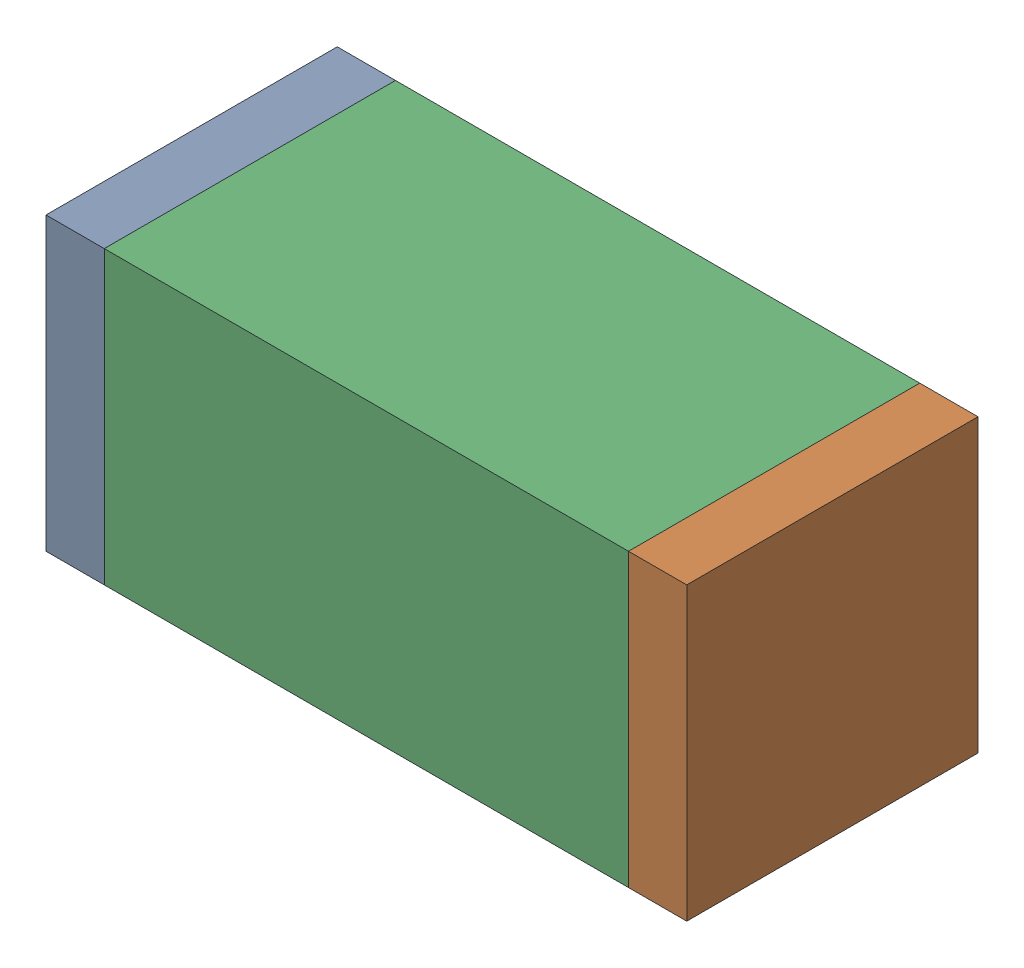
SolidWorks assembly R81, configuration Default. Lengths in mm.
Overall size (1.1 0.5 0.5).
6 component instances, 2 part files, 0 mates.
Components (placement in the parent):
- 810156080-1: 810156080 [Default] at (131.9498 29.7142 0) size (0.1 0.5 0.5)
  - Extruded_5-1: Extruded_5 [Default] at origin size (0.1 0.5 0.5)
- 810156080-2: 810156080 [Default] at (132.9497 29.7142 0) size (0.1 0.5 0.5)
  - Extruded_5-1: Extruded_5 [Default] at origin size (0.1 0.5 0.5)
- 836749680-1: 836749680 [Default] at (132.4498 29.7142 0) size (0.9 0.5 0.5)
  - Extruded_4-1: Extruded_4 [Default] at origin size (0.9 0.5 0.5)
